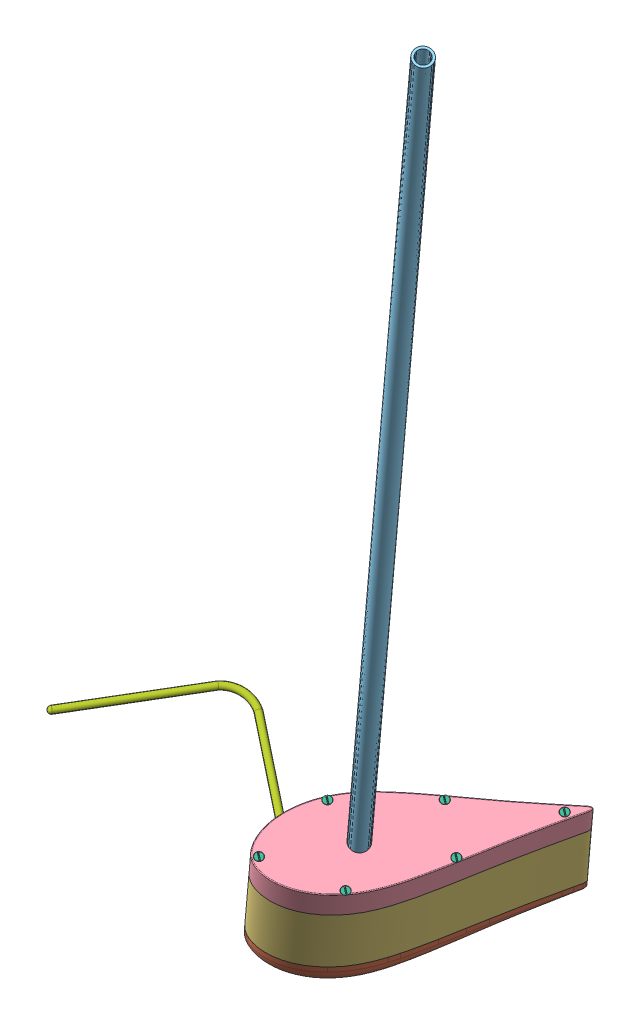
SolidWorks assembly Velocity Sensor V2.0, configuration Default. Lengths in mm.
Overall size (879.23 1542.98 729.31).
12 component instances, 7 part files, 25 mates.
Components (placement in the parent):
- 655A-07-C-1: 655A-07-C [Default] at (-41.471 27.2619 2.0651) x (0.572506 0.052511 -0.818217) z (0.736975 -0.470296 0.485479) size (72 169 64.25)
- Lower End Cap-1: Lower End Cap [Default] at (-96.3866 23.073 81.3711) x (0.572506 0.052511 -0.818217) z (0.736975 -0.470296 0.485479) size (300.08 58.74 97.47)
- MidUnit-Eppler862-1: MidUnit-Eppler862 [Default] at (-92.7935 31.8824 84.4506) x (0.572506 0.052511 -0.818217) z (0.736975 -0.470296 0.485479) size (300.89 100.01 97.46)
- UppeCap-Eppler862-1: UppeCap-Eppler862 [Default] at (-56.8624 119.9769 115.2453) x (0.572506 0.052511 -0.818217) z (0.736975 -0.470296 0.485479) size (319.12 57.64 129.29)
- Strut-1: Strut [Default] at (555.5361 1493.0729 515.7569) x (0.931362 -0.359311 -0.058826) z (-0.359311 -0.880945 -0.307947) size (21.34 21.34 1524)
- 10-24 Thread Size_6in Long-1: 10-24 Thread Size_6in Long [91781A269] at (31.6412 134.8659 86.4641) x (-0.747533 0.469234 -0.470121) z (0.359311 0.880945 0.307947) size (9.12 9.19 152.95)
- 10-24 Thread Size_6in Long-2: 10-24 Thread Size_6in Long [91781A269] at (-33.581 176.4871 43.4992) x (-0.747533 0.469234 -0.470121) z (0.359311 0.880945 0.307947) size (9.12 9.19 152.95)
- 10-24 Thread Size_6in Long-3: 10-24 Thread Size_6in Long [91781A269] at (35.4612 174.2135 -30.5548) x (-0.747533 0.469234 -0.470121) z (0.359311 0.880945 0.307947) size (9.12 9.19 152.95)
- 10-24 Thread Size_6in Long-4: 10-24 Thread Size_6in Long [91781A269] at (77.1003 147.6418 -3.1253) x (-0.747533 0.469234 -0.470121) z (0.359311 0.880945 0.307947) size (9.12 9.19 152.95)
- 10-24 Thread Size_6in Long-5: 10-24 Thread Size_6in Long [91781A269] at (113.5314 166.1788 -98.6617) x (-0.747533 0.469234 -0.470121) z (0.359311 0.880945 0.307947) size (9.12 9.19 152.95)
- 10-24 Thread Size_6in Long-6: 10-24 Thread Size_6in Long [91781A269] at (-39.9004 152.1057 120.6204) x (-0.747533 0.469234 -0.470121) z (0.359311 0.880945 0.307947) size (9.12 9.19 152.95)
- Pitot Tube-1: Pitot Tube [Default] at (-57.4418 84.5596 60.7627) x (-0.572506 -0.052511 0.818217) z (-0.736975 0.470296 -0.485479) size (197.35 12.7 237.01)
Mates (geometry in assembly coordinates):
- Concentric4: concentric anti-aligned: cylinder of 655A-07-C-1 through (-54.6386 26.0542 20.8841) axis (0.572506 0.052511 -0.818217) radius 32; cylinder of Lower End Cap-1 through (30.9566 33.9051 -101.4472) axis (-0.572506 -0.052511 0.818217) radius 32
- Coincident3: coincident anti-aligned: plane of 655A-07-C-1 through (-54.6386 26.0542 20.8841) normal (-0.572506 -0.052511 0.818217); plane of Lower End Cap-1 through (-54.6386 26.0542 20.8841) normal (0.572506 0.052511 -0.818217)
- Concentric6: concentric anti-aligned: cylinder of Lower End Cap-1 through (-17.2444 15.0101 44.5667) axis (-0.359311 -0.880945 -0.307947) radius 2.415; cylinder of MidUnit-Eppler862-1 through (-19.6987 8.9927 42.4633) axis (0.359311 0.880945 0.307947) radius 2.415
- Concentric7: concentric anti-aligned: cylinder of Lower End Cap-1 through (-82.4666 56.6314 1.6019) axis (-0.359311 -0.880945 -0.307947) radius 2.415; cylinder of MidUnit-Eppler862-1 through (-84.921 50.6139 -0.5016) axis (0.359311 0.880945 0.307947) radius 2.415
- Coincident9: coincident anti-aligned: plane of Lower End Cap-1 through (-92.7935 31.8824 84.4506) normal (0.359311 0.880945 0.307947); plane of MidUnit-Eppler862-1 through (78.9585 47.6358 -161.0145) normal (-0.359311 -0.880945 -0.307947)
- Coincident10: coincident anti-aligned: plane of MidUnit-Eppler862-1 through (114.8896 135.7303 -130.2198) normal (0.359311 0.880945 0.307947); plane of UppeCap-Eppler862-1 through (114.8896 135.7303 -130.2198) normal (-0.359311 -0.880945 -0.307947)
- Concentric10: concentric anti-aligned: cylinder of UppeCap-Eppler862-1 through (11.5389 159.3223 49.5246) axis (-0.359311 -0.880945 -0.307947) radius 10.668; cylinder of Strut-1 through (7.9458 150.5129 46.4452) axis (0.359311 0.880945 0.307947) radius 10.668
- Coincident11: coincident aligned: plane of UppeCap-Eppler862-1 through (125.3096 161.2777 -121.2893) normal (-0.359311 -0.880945 -0.307947); plane of Strut-1 through (7.9458 150.5129 46.4452) normal (-0.359311 -0.880945 -0.307947)
- Concentric11: concentric aligned: cylinder of UppeCap-Eppler862-1 through (32.6999 137.4615 87.3714) axis (0.359311 0.880945 0.307947) radius 2.5527; cylinder of 10-24 Thread Size_6in Long-1 through (32.6999 137.4615 87.3714) axis (0.359311 0.880945 0.307947) radius 2.413
- Coincident12: coincident aligned: plane of 10-24 Thread Size_6in Long-2 through (-33.8704 178.9348 46.4024) normal (0.359311 0.880945 0.307947); plane of 10-24 Thread Size_6in Long-3 through (35.1718 176.6612 -27.6516) normal (0.359311 0.880945 0.307947)
- Coincident13: coincident aligned: plane of 10-24 Thread Size_6in Long-3 through (35.1718 176.6612 -27.6516) normal (0.359311 0.880945 0.307947); plane of 10-24 Thread Size_6in Long-4 through (76.8109 150.0895 -0.222) normal (0.359311 0.880945 0.307947)
- Coincident14: coincident aligned: plane of 10-24 Thread Size_6in Long-4 through (76.8109 150.0895 -0.222) normal (0.359311 0.880945 0.307947); plane of 10-24 Thread Size_6in Long-5 through (113.242 168.6265 -95.7585) normal (0.359311 0.880945 0.307947)
- Coincident15: coincident: plane of 10-24 Thread Size_6in Long-5 through (113.242 168.6265 -95.7585) normal (0.359311 0.880945 0.307947); line of 10-24 Thread Size_6in Long-6 through (-35.753 152.5258 124.1475) axis (-0.747533 0.469234 -0.470121)
- Coincident16: coincident aligned: plane of 10-24 Thread Size_6in Long-1 through (31.3519 137.3136 89.3673) normal (0.359311 0.880945 0.307947); plane of 10-24 Thread Size_6in Long-6 through (-40.1897 154.5534 123.5236) normal (0.359311 0.880945 0.307947)
- Concentric12: concentric aligned: circle of UppeCap-Eppler862-1; cylinder of 10-24 Thread Size_6in Long-6 through (-38.8417 154.7013 121.5277) axis (0.359311 0.880945 0.307947) radius 2.413
- Concentric13: concentric aligned: circle of UppeCap-Eppler862-1; cylinder of 10-24 Thread Size_6in Long-2 through (-32.5224 179.0827 44.4066) axis (0.359311 0.880945 0.307947) radius 2.413
- Concentric14: concentric aligned: circle of UppeCap-Eppler862-1; cylinder of 10-24 Thread Size_6in Long-3 through (36.5199 176.8091 -29.6475) axis (0.359311 0.880945 0.307947) radius 2.413
- Concentric15: concentric aligned: circle of UppeCap-Eppler862-1; cylinder of 10-24 Thread Size_6in Long-4 through (78.1589 150.2374 -2.2179) axis (0.359311 0.880945 0.307947) radius 2.413
- Concentric16: concentric aligned: circle of UppeCap-Eppler862-1; cylinder of 10-24 Thread Size_6in Long-5 through (114.5901 168.7744 -97.7544) axis (0.359311 0.880945 0.307947) radius 2.413
- Concentric17: concentric aligned: cylinder of MidUnit-Eppler862-1 through (-19.6987 8.9927 42.4633) axis (0.359311 0.880945 0.307947) radius 2.415; cylinder of UppeCap-Eppler862-1 through (32.6999 137.4615 87.3714) axis (0.359311 0.880945 0.307947) radius 2.5527
- Concentric18: concentric anti-aligned: circle of MidUnit-Eppler862-1; cylinder of UppeCap-Eppler862-1 through (-32.5224 179.0827 44.4066) axis (0.359311 0.880945 0.307947) radius 2.5527
- Coincident17: coincident aligned: plane of UppeCap-Eppler862-1 through (128.9027 170.0872 -118.2098) normal (0.359311 0.880945 0.307947); plane of 10-24 Thread Size_6in Long-1 through (31.3519 137.3136 89.3673) normal (0.359311 0.880945 0.307947)
- Coincident18: coincident aligned: plane of 655A-07-C-1 through (-40.9866 28.3012 34.2472) normal (0.359311 0.880945 0.307947); plane of Lower End Cap-1 through (-92.7935 31.8824 84.4506) normal (0.359311 0.880945 0.307947)
- Parallel1: parallel aligned: plane of UppeCap-Eppler862-1 through (128.9027 170.0872 -118.2098) normal (0.359311 0.880945 0.307947); plane of Pitot Tube-1 through (-44.0561 80.4142 77.6235) normal (0.359311 0.880945 0.307947)
- Parallel3: parallel aligned: plane of 655A-07-C-1 through (-41.471 27.2619 2.0651) normal (0.736975 -0.470296 0.485479); plane of Pitot Tube-1 through (-42.7023 75.1536 70.4723) normal (0.736975 -0.470296 0.485479)
